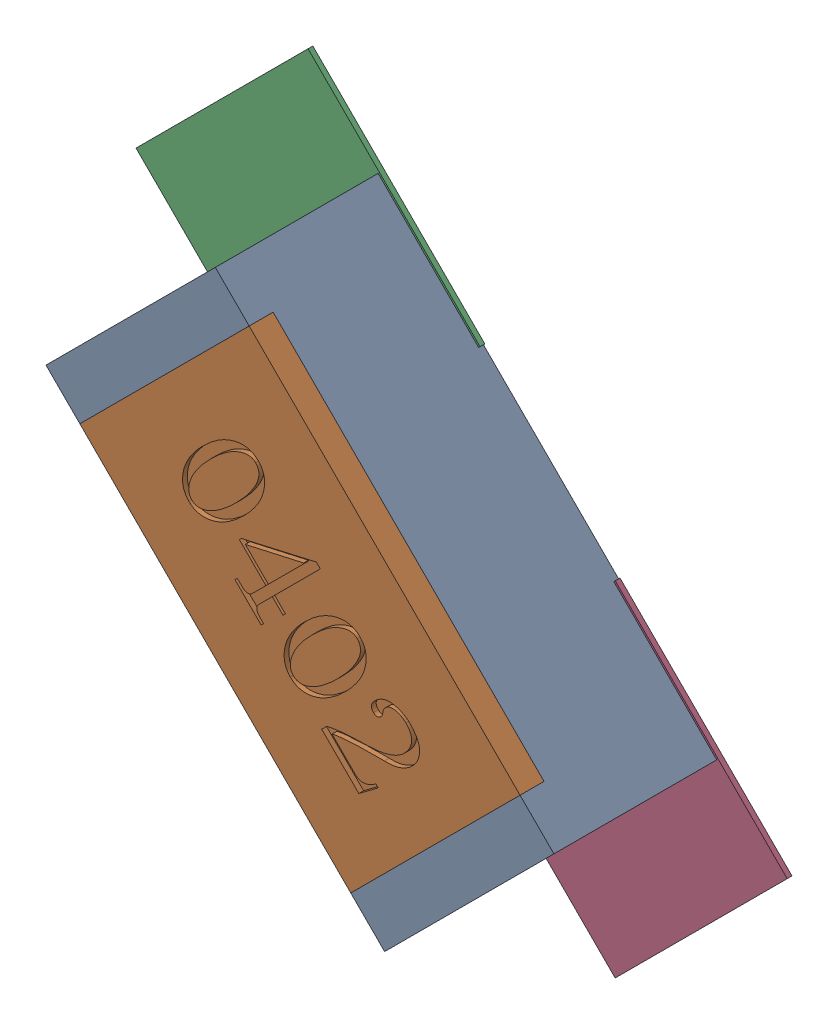
SolidWorks assembly R120, configuration Défaut. Lengths in mm.
Overall size (1.36 1.36 0.35).
5 component instances, 2 part files, 0 mates.
Components (placement in the parent):
- R0402-1: R0402 [Défaut] at (74.9523 -16.4358 0) x (0.707107 -0.707107 0) z (0 0 1) size (1 0.5 0.35)
- 8260096304-1: 8260096304 [Défaut] at (74.6292 -16.1125 0) size (0.72 0.72 0.01)
  - Extruded_694-1: Extruded_694 [Défaut] at origin size (0.72 0.72 0.01)
- 8260096304-2: 8260096304 [Défaut] at (75.2706 -16.754 0) size (0.72 0.72 0.01)
  - Extruded_694-1: Extruded_694 [Défaut] at origin size (0.72 0.72 0.01)
